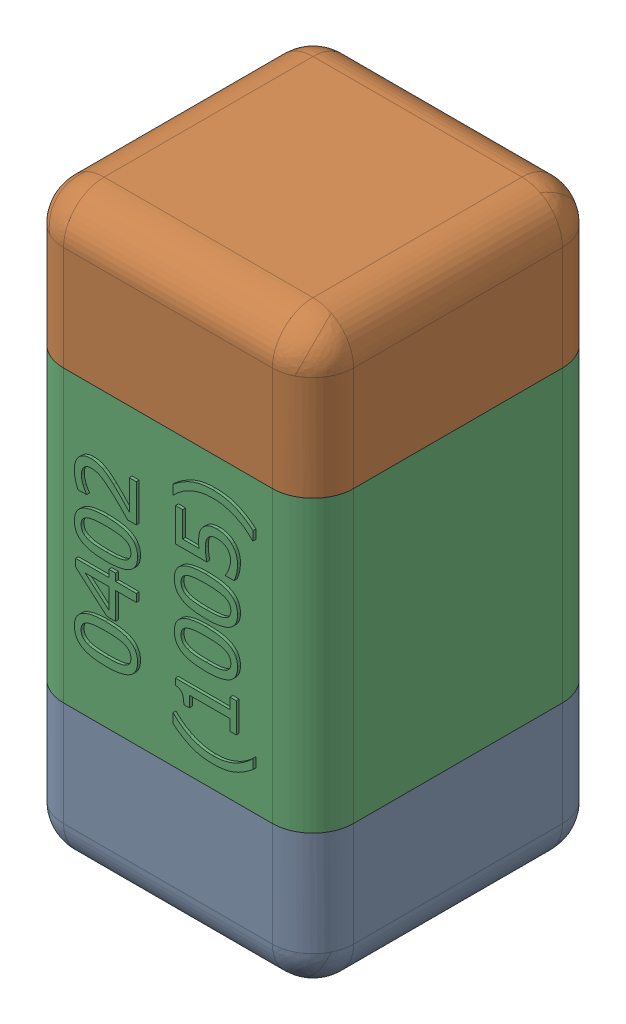
SolidWorks assembly C41, configuration Standard. Lengths in mm.
Overall size (0.51 1.01 0.51).
4 component instances, 3 part files, 0 mates.
Components (placement in the parent):
- C41-subassembly-1-1: C41-subassembly-1 [Standard] at (-8.3 13.9001 0) x (0 1 0) z (0 0 1) size (1.01 0.51 0.51)
  - User Library-0402_Cap-1: User Library-0402_Cap [Standard] at origin size (0.26 0.51 0.51)
  - User Library-0402_Cap-1-1: User Library-0402_Cap-1 [Standard] at origin size (0.26 0.5 0.51)
  - User Library-0402_Cap-2-1: User Library-0402_Cap-2 [Standard] at origin size (0.5 0.5 0.51)
